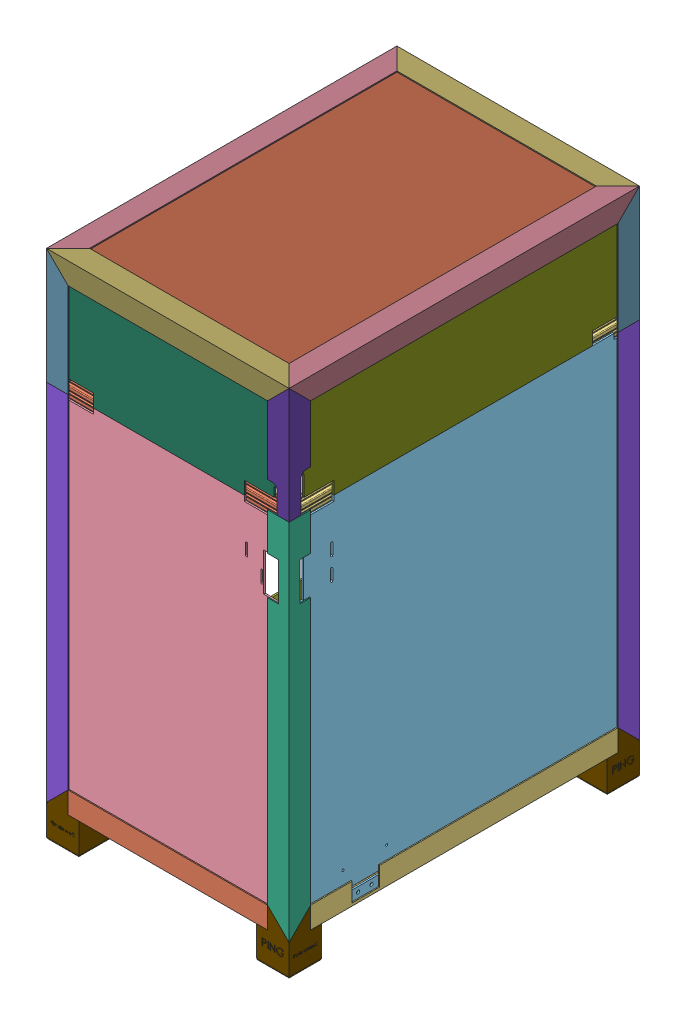
SolidWorks assembly carcasse, configuration Défaut. Lengths in mm.
Overall size (450.38 950 650.19).
53 component instances, 24 part files, 67 mates.
Components (placement in the parent):
- cadre-1: cadre [Défaut] at (-215.194 -19.8636 -400) size (448.16 24.28 648.16)
  - Blocks-1: Blocks [Défaut] at (-153.6103 82.5412 1245.1575) x (0 1 0) z (0 0 1) size (20 20 20)
  - Blocks-3: Blocks [Défaut] at (-153.6103 62.5412 625.1575) x (0 0 -1) z (0 1 0) size (20 20 20)
  - Blocks-4: Blocks [Défaut] at (246.3897 82.5412 645.1575) x (0 1 0) z (0 0 -1) size (20 20 20)
  - Blocks-5: Blocks [Défaut] at (246.3897 62.5412 1265.1575) x (0 0 1) z (0 1 0) size (20 20 20)
  - prof_20x20x400mm-1: prof_20x20x400mm [End Finishing_Non-Machined End Finish Options_Type_Single_] at (246.3897 72.5412 635.1575) x (0 0 1) z (-1 0 0) size (28.16 24.28 400)
  - prof_20x20x400mm-2: prof_20x20x400mm [End Finishing_Non-Machined End Finish Options_Type_Single_] at (246.3897 72.5412 1255.1575) x (0 0 1) z (-1 0 0) size (28.16 24.28 400)
  - prof_20x20x600mm-4: prof_20x20x600mm [End Finishing_Non-Machined End Finish Options_Type_Single_] at (256.3897 72.5412 645.1575) size (28.16 24.28 600)
  - prof_20x20x600mm-5: prof_20x20x600mm [End Finishing_Non-Machined End Finish Options_Type_Single_] at (-163.6103 72.5412 645.1575) size (28.16 24.28 600)
- prof_20x20x640mm-1: prof_20x20x640mm [End Finishing_Non-Machined End Finish Options_Type_Single_] at (41.1957 42.6776 235.1575) x (1 0 0) z (0 -1 0) size (28.16 24.28 640)
- prof_20x20x640mm-2: prof_20x20x640mm [End Finishing_Non-Machined End Finish Options_Type_Single_] at (41.1957 42.6776 855.1575) x (1 0 0) z (0 -1 0) size (28.16 24.28 640)
- prof_20x20x640mm-3: prof_20x20x640mm [End Finishing_Non-Machined End Finish Options_Type_Single_] at (-378.8043 42.6776 855.1575) x (1 0 0) z (0 -1 0) size (28.16 24.28 640)
- prof_20x20x640mm-4: prof_20x20x640mm [End Finishing_Non-Machined End Finish Options_Type_Single_] at (-378.8043 42.6776 235.1575) x (1 0 0) z (0 -1 0) size (28.16 24.28 640)
- cadre-2: cadre [Défaut] at (-122.4146 -534.7812 -400) x (-1 0 0) z (0 0 1) size (448.16 24.28 648.16)
  - Blocks-1: Blocks [Défaut] at (-153.6103 82.5412 1245.1575) x (0 1 0) z (0 0 1) size (20 20 20)
  - Blocks-3: Blocks [Défaut] at (-153.6103 62.5412 625.1575) x (0 0 -1) z (0 1 0) size (20 20 20)
  - Blocks-4: Blocks [Défaut] at (246.3897 82.5412 645.1575) x (0 1 0) z (0 0 -1) size (20 20 20)
  - Blocks-5: Blocks [Défaut] at (246.3897 62.5412 1265.1575) x (0 0 1) z (0 1 0) size (20 20 20)
  - prof_20x20x400mm-1: prof_20x20x400mm [End Finishing_Non-Machined End Finish Options_Type_Single_] at (246.3897 72.5412 635.1575) x (0 0 1) z (-1 0 0) size (28.16 24.28 400)
  - prof_20x20x400mm-2: prof_20x20x400mm [End Finishing_Non-Machined End Finish Options_Type_Single_] at (246.3897 72.5412 1255.1575) x (0 0 1) z (-1 0 0) size (28.16 24.28 400)
  - prof_20x20x600mm-4: prof_20x20x600mm [End Finishing_Non-Machined End Finish Options_Type_Single_] at (256.3897 72.5412 645.1575) size (28.16 24.28 600)
  - prof_20x20x600mm-5: prof_20x20x600mm [End Finishing_Non-Machined End Finish Options_Type_Single_] at (-163.6103 72.5412 645.1575) size (28.16 24.28 600)
- plaque_acrylique_680x670-2: plaque_acrylique_680x670 [Défaut] at (51.1957 -282.3224 525.1575) x (0 0 -1) z (1 0 0) size (640 670 3)
- plaque_acrylique_380x670_G-1: plaque_acrylique_380x670_G [Défaut] at (-138.8043 -282.3224 222.1575) size (440 670 3)
- plaque_acrylique_680x670_porte-1: plaque_acrylique_680x670_porte [Défaut] at (-391.8043 -282.3224 525.1575) x (0 0 -1) z (1 0 0) size (640 670 3)
- eclisse_40x40x670_bisote_x1-1: eclisse_40x40x670_bisote_x1 [Défaut] at (-373.8043 -622.3224 240.2711) size (40 675 40)
- eclisse_40x40x670_bisote_x1-2: eclisse_40x40x670_bisote_x1 [Défaut] at (-373.6907 -622.3224 850.1575) x (0 0 -1) z (1 0 0) size (40 675 40)
- eclisse_40x40x670_bisote_x1-4: eclisse_40x40x670_bisote_x1 [Défaut] at (36.0821 -622.3224 240.1575) x (0 0 1) z (-1 0 0) size (40 675 40)
- couvercle-1: couvercle [Défaut] at (303.0646 123.7676 738.5466) size (450 215 650)
  - plaque_acrylique_680x210-2: plaque_acrylique_680x210 [Défaut] at (-694.8689 33.91 -173.3892) x (0 0 -1) z (1 0 0) size (640 210 3)
  - plaque_acrylique_380x210-2: plaque_acrylique_380x210 [Défaut] at (-441.8689 33.91 -516.3892) size (440 210 3)
  - plaque_acrylique_380x680-1: plaque_acrylique_380x680 [Défaut] at (-441.8689 138.91 -173.3892) x (1 0 0) z (0 1 0) size (440 640 3)
  - eclisse_40x40x404_bisote_x2-1: eclisse_40x40x404_bisote_x2 [Défaut] at (-246.8689 123.7964 -498.3892) x (0 0 1) z (0 -1 0) size (40 450 40)
  - eclisse_40x40x704_bisote_x2-1: eclisse_40x40x704_bisote_x2 [Défaut] at (-266.9825 123.91 -518.3892) x (0 -1 0) z (-1 0 0) size (40 650 40)
  - eclisse_40x40x404_bisote_x2-2: eclisse_40x40x404_bisote_x2 [Défaut] at (-696.8689 123.7964 111.6108) x (0 0 -1) z (0 -1 0) size (40 450 40)
  - eclisse_40x40x704_bisote_x2-2: eclisse_40x40x704_bisote_x2 [Défaut] at (-676.8689 123.7964 -518.3892) x (1 0 0) z (0 -1 0) size (40 650 40)
  - eclisse_40x40x222_bisote_x1-1: eclisse_40x40x222_bisote_x1 [Défaut] at (-676.7552 143.91 -498.3892) x (0 0 1) z (1 0 0) size (40 215 40)
  - eclisse_40x40x222_bisote_x1-2: eclisse_40x40x222_bisote_x1 [Défaut] at (-266.8689 143.91 -498.2755) x (-1 0 0) z (0 0 1) size (40 215 40)
  - eclisse_40x40x222_bisote_x1-4: eclisse_40x40x222_bisote_x1 [Défaut] at (-676.8689 143.91 111.4972) x (1 0 0) z (0 0 -1) size (40 215 40)
  - plaque_acrylique_380x210_Moteur-1: plaque_acrylique_380x210_Moteur [Défaut] at (-441.8689 33.91 126.6108) size (440 210 3)
  - plaque_acrylique_680x210_moteur-1: plaque_acrylique_680x210_moteur [Défaut] at (-251.8689 33.91 -173.3892) x (0 0 -1) z (1 0 0) size (640 210 3)
  - eclisse_40x40x222_bisote_x1_Moteur-1: eclisse_40x40x222_bisote_x1_Moteur [Défaut] at (-266.9825 143.91 111.6108) x (0 0 -1) z (-1 0 0) size (40 215 40)
- Pied-1: Pied [Défaut] at (-3.8043 -622.3224 280.1575) x (-1 0 0) z (0 -1 0) size (60 60 100)
- Pied-2: Pied [Défaut] at (-3.8043 -622.3224 810.1575) x (0 0 -1) z (0 -1 0) size (60 60 100)
- Pied-3: Pied [Défaut] at (-333.8043 -622.3224 810.1575) x (1 0 0) z (0 -1 0) size (60 60 100)
- Pied-4: Pied [Défaut] at (-333.8043 -622.3224 280.1575) x (0 0 1) z (0 -1 0) size (60 60 100)
- eclisse_bas_40x40x704-2: eclisse_bas_40x40x704 [Défaut] at (-373.8043 -602.2087 830.1575) x (1 0 0) z (0 1 0) size (40 570 40)
- eclisse_bas_40x40x404-1: eclisse_bas_40x40x404 [Défaut] at (-353.8043 -602.2087 240.1575) x (0 0 1) z (0 1 0) size (40 370 40)
- eclisse_bas_40x40x404-2: eclisse_bas_40x40x404 [Défaut] at (16.1957 -602.2087 850.1575) x (0 0 -1) z (0 1 0) size (40 370 40)
- eclisse_bas_support_Z_40x40x704-1: eclisse_bas_support_Z_40x40x704 [Défaut] at (36.0821 -602.3224 830.1575) x (0 1 0) z (-1 0 0) size (40 570 40)
- plaque_acrylique_380x670_D-2: plaque_acrylique_380x670_D [Défaut] at (-198.8043 -282.3224 868.1575) x (-1 0 0) z (0 0 -1) size (440 670 3)
- plaque_acrylique_bas_380x680-1: plaque_acrylique_bas_380x680 [Défaut] at (-138.8043 -620.3224 565.1575) x (1 0 0) z (0 1 0) size (440 640 3)
- eclisse_40x40x670_bisote_x1-Moteur-1: eclisse_40x40x670_bisote_x1-Moteur [Défaut] at (36.1957 -622.3224 850.0438) x (-1 0 0) z (0 0 -1) size (40 675 40)
Mates (geometry in assembly coordinates):
- Coïncidente66: coincident anti-aligned: plane of plaque_acrylique_680x670_porte-1 through (-391.8043 -282.3224 525.1575) normal (-1 0 0); plane of eclisse_40x40x670_bisote_x1-1 through (-391.8043 52.6776 222.1575) normal (1 0 0)
- Coïncidente67: coincident aligned: plane of plaque_acrylique_680x670_porte-1 through (-388.8043 52.6776 865.1575) normal (0 1 0); plane of eclisse_40x40x670_bisote_x1-1 through (-373.8043 52.6776 240.2711) normal (0 1 0)
- Coïncidente68: coincident anti-aligned: plane of plaque_acrylique_680x670-2 through (54.1957 -282.3224 525.1575) normal (1 0 0); plane of eclisse_40x40x670_bisote_x1-4 through (54.1957 52.6776 222.1575) normal (-1 0 0)
- Coïncidente72: coincident anti-aligned: plane of plaque_acrylique_680x670_porte-1 through (-391.8043 -282.3224 525.1575) normal (-1 0 0); plane of eclisse_40x40x670_bisote_x1-2 through (-391.8043 52.6776 868.1575) normal (1 0 0)
- Coïncidente100: coincident: plane of plaque_acrylique_680x670_porte-1 through (-388.8043 52.6776 865.1575) normal (0 1 0); line of eclisse_40x40x670_bisote_x1-2 through (-391.8043 52.6776 868.1575) axis (0 0 -1)
- Coïncidente130: coincident anti-aligned: plane of eclisse_40x40x670_bisote_x1-2 through (196.1957 -622.3224 870.1575) normal (0 -0.707107 -0.707107); plane of Pied-3 through (-391.8043 -582.3224 830.1575) normal (0 0.707107 0.707107)
- Coïncidente132: coincident anti-aligned: plane of plaque_acrylique_680x670_porte-1 through (-391.8043 -282.3224 525.1575) normal (-1 0 0); plane of eclisse_bas_40x40x704-2 through (-391.8043 -620.3224 260.1575) normal (1 0 0)
- Coïncidente134: coincident anti-aligned: line of eclisse_40x40x670_bisote_x1-2 through (-393.8043 52.6776 830.1575) axis (0 -1 0); line of eclisse_bas_40x40x704-2 through (-393.8043 -622.3224 830.1575) axis (0 1 0)
- Coïncidente140: coincident anti-aligned: line of Pied-3 through (-353.8043 -582.3224 870.1575) axis (0 -1 0); line of eclisse_bas_40x40x404-2 through (-353.8043 -622.3224 870.1575) axis (0 1 0)
- Coïncidente142: coincident anti-aligned: plane of plaque_acrylique_680x670-2 through (54.1957 -282.3224 525.1575) normal (1 0 0); plane of eclisse_bas_support_Z_40x40x704-1 through (54.1957 -620.3224 260.1575) normal (-1 0 0)
- Coïncidente144: coincident anti-aligned: plane of Pied-2 through (54.1957 -582.3224 830.1575) normal (0 0 -1); plane of eclisse_bas_support_Z_40x40x704-1 through (36.0821 -602.3224 830.1575) normal (0 0 1)
- Coïncidente156: coincident anti-aligned: plane of eclisse_bas_40x40x404-2 through (-353.8043 -620.3224 868.1575) normal (0 0 -1); plane of plaque_acrylique_380x670_D-2 through (-198.8043 -282.3224 868.1575) normal (0 0 1)
- Coïncidente157: coincident anti-aligned: plane of eclisse_40x40x670_bisote_x1-2 through (-391.8043 52.6776 868.1575) normal (0 0 -1); plane of plaque_acrylique_380x670_D-2 through (-198.8043 -282.3224 868.1575) normal (0 0 1)
- Coïncidente163: coincident anti-aligned: plane of cadre-1/Blocks-1 through (-388.8043 42.6776 865.1575) normal (0 -1 0); plane of prof_20x20x640mm-3 through (-387.3043 42.6776 863.6575) normal (0 1 0)
- Coïncidente164: coincident aligned: plane of cadre-1/Blocks-1 through (-388.8043 42.6776 865.1575) normal (-1 0 0); plane of prof_20x20x640mm-3 through (-388.8043 -597.3224 858.9075) normal (-1 0 0)
- Coïncidente165: coincident aligned: plane of cadre-1/Blocks-1 through (-368.8043 62.6776 865.1575) normal (0 0 1); plane of prof_20x20x640mm-3 through (-382.5543 -597.3224 865.1575) normal (0 0 1)
- Coïncidente166: coincident anti-aligned: plane of prof_20x20x640mm-3 through (-387.3043 -597.3224 863.6575) normal (0 -1 0); plane of cadre-2/Blocks-5 through (-368.8043 -597.3224 865.1575) normal (0 1 0)
- Coïncidente167: coincident aligned: plane of prof_20x20x640mm-3 through (-382.5543 -597.3224 865.1575) normal (0 0 1); plane of cadre-2/Blocks-5 through (-388.8043 -617.3224 865.1575) normal (0 0 1)
- Coïncidente168: coincident aligned: plane of prof_20x20x640mm-3 through (-388.8043 -597.3224 858.9075) normal (-1 0 0); plane of cadre-2/Blocks-5 through (-388.8043 -617.3224 845.1575) normal (-1 0 0)
- Coïncidente169: coincident anti-aligned: plane of prof_20x20x640mm-2 through (32.6957 -597.3224 863.6575) normal (0 -1 0); plane of cadre-2/Blocks-1 through (51.1957 -597.3224 865.1575) normal (0 1 0)
- Coïncidente170: coincident aligned: plane of prof_20x20x640mm-2 through (37.4457 -597.3224 865.1575) normal (0 0 1); plane of cadre-2/Blocks-1 through (31.1957 -617.3224 865.1575) normal (0 0 1)
- Coïncidente171: coincident aligned: plane of prof_20x20x640mm-2 through (51.1957 -597.3224 858.9075) normal (1 0 0); plane of cadre-2/Blocks-1 through (51.1957 -597.3224 865.1575) normal (1 0 0)
- Coïncidente172: coincident anti-aligned: plane of prof_20x20x640mm-1 through (32.6957 -597.3224 243.6575) normal (0 -1 0); plane of cadre-2/Blocks-3 through (31.1957 -597.3224 225.1575) normal (0 1 0)
- Coïncidente173: coincident aligned: plane of prof_20x20x640mm-1 through (51.1957 -597.3224 238.9075) normal (1 0 0); plane of cadre-2/Blocks-3 through (51.1957 -617.3224 245.1575) normal (1 0 0)
- Coïncidente174: coincident aligned: plane of prof_20x20x640mm-1 through (44.9457 -597.3224 225.1575) normal (0 0 -1); plane of cadre-2/Blocks-3 through (51.1957 -617.3224 225.1575) normal (0 0 -1)
- Coïncidente175: coincident aligned: plane of cadre-1/Blocks-3 through (-388.8043 62.6776 245.1575) normal (-1 0 0); plane of prof_20x20x640mm-4 through (-388.8043 -597.3224 231.4075) normal (-1 0 0)
- Coïncidente176: coincident aligned: plane of cadre-1/Blocks-3 through (-388.8043 62.6776 225.1575) normal (0 0 -1); plane of prof_20x20x640mm-4 through (-382.5543 -597.3224 225.1575) normal (0 0 -1)
- Coïncidente177: coincident anti-aligned: plane of cadre-1/Blocks-3 through (-368.8043 42.6776 225.1575) normal (0 -1 0); plane of prof_20x20x640mm-4 through (-387.3043 42.6776 243.6575) normal (0 1 0)
- Coïncidente183: coincident aligned: plane of prof_20x20x640mm-2 through (51.1957 -597.3224 858.9075) normal (1 0 0); plane of plaque_acrylique_380x670_D-2 through (51.1957 52.6776 865.1575) normal (1 0 0)
- Coïncidente186: coincident aligned: plane of cadre-1/prof_20x20x400mm-2 through (-368.8043 56.4276 865.1575) normal (0 0 1); plane of plaque_acrylique_680x670-2 through (54.1957 52.6776 865.1575) normal (0 0 1)
- Coïncidente187: coincident aligned: plane of cadre-1/prof_20x20x400mm-1 through (-368.8043 48.9276 225.1575) normal (0 0 -1); plane of plaque_acrylique_680x670_porte-1 through (-388.8043 52.6776 225.1575) normal (0 0 -1)
- Coïncidente191: coincident anti-aligned: plane of cadre-2/prof_20x20x400mm-1 through (31.1957 -617.3224 238.9075) normal (0 -1 0); plane of plaque_acrylique_bas_380x680-1 through (-138.8043 -617.3224 565.1575) normal (0 1 0)
- Coïncidente192: coincident aligned: plane of cadre-2/prof_20x20x400mm-2 through (31.1957 -611.0724 865.1575) normal (0 0 1); plane of plaque_acrylique_bas_380x680-1 through (-388.8043 -617.3224 865.1575) normal (0 0 1)
- Coïncidente199: coincident anti-aligned: line of eclisse_40x40x670_bisote_x1-4 through (56.1957 -622.3224 220.1575) axis (0 0.707107 0.707107); line of Pied-1 through (56.1957 -582.3224 260.1575) axis (0 -0.707107 -0.707107)
- Coïncidente201: coincident anti-aligned: plane of plaque_acrylique_680x670-2 through (54.1957 -282.3224 525.1575) normal (1 0 0); plane of Pied-2 through (54.1957 -582.3224 868.1575) normal (-1 0 0)
- Coïncidente204: coincident anti-aligned: plane of prof_20x20x640mm-1 through (44.9457 -597.3224 225.1575) normal (0 0 -1); plane of plaque_acrylique_380x670_G-1 through (-138.8043 -282.3224 225.1575) normal (0 0 1)
- Coïncidente205: coincident aligned: plane of cadre-2/prof_20x20x400mm-1 through (31.1957 -617.3224 231.4075) normal (0 -1 0); plane of plaque_acrylique_380x670_G-1 through (-388.8043 -617.3224 225.1575) normal (0 -1 0)
- Coïncidente206: coincident aligned: plane of prof_20x20x640mm-1 through (51.1957 -597.3224 231.4075) normal (1 0 0); plane of plaque_acrylique_380x670_G-1 through (51.1957 52.6776 225.1575) normal (1 0 0)
- Coïncidente207: coincident anti-aligned: plane of prof_20x20x640mm-4 through (-388.8043 -597.3224 231.4075) normal (-1 0 0); plane of plaque_acrylique_680x670_porte-1 through (-388.8043 -282.3224 525.1575) normal (1 0 0)
- Coïncidente208: coincident anti-aligned: plane of plaque_acrylique_380x670_G-1 through (-138.8043 -282.3224 222.1575) normal (0 0 -1); plane of eclisse_40x40x670_bisote_x1-1 through (-391.8043 52.6776 222.1575) normal (0 0 1)
- Coïncidente210: coincident anti-aligned: plane of plaque_acrylique_380x670_G-1 through (-138.8043 -282.3224 222.1575) normal (0 0 -1); plane of eclisse_40x40x670_bisote_x1-4 through (54.1957 52.6776 222.1575) normal (0 0 1)
- Parallèle4: parallel anti-aligned: line of eclisse_40x40x670_bisote_x1-1 through (-393.8043 -622.3224 220.1575) axis (0.707107 0.707107 0); line of Pied-4 through (-353.8043 -582.3224 220.1575) axis (-0.707107 -0.707107 0)
- Coïncidente218: coincident: plane of cadre-2/prof_20x20x400mm-2 through (31.1957 -617.3224 858.9075) normal (0 -1 0); line of plaque_acrylique_380x670_D-2 through (51.1957 -617.3224 868.1575) axis (-1 0 0)
- Coïncidente223: coincident anti-aligned: plane of eclisse_bas_support_Z_40x40x704-1 through (54.1957 -620.3224 260.1575) normal (0 1 0); plane of plaque_acrylique_bas_380x680-1 through (-138.8043 -620.3224 565.1575) normal (0 -1 0)
- Coïncidente224: coincident anti-aligned: plane of eclisse_bas_40x40x704-2 through (-391.8043 -620.3224 260.1575) normal (0 1 0); plane of plaque_acrylique_bas_380x680-1 through (-138.8043 -620.3224 565.1575) normal (0 -1 0)
- Coïncidente225: coincident anti-aligned: plane of plaque_acrylique_380x670_G-1 through (-138.8043 -282.3224 222.1575) normal (0 0 -1); plane of eclisse_bas_40x40x404-1 through (16.1957 -620.3224 222.1575) normal (0 0 1)
- Coïncidente226: coincident anti-aligned: plane of eclisse_bas_40x40x404-1 through (16.1957 -620.3224 222.1575) normal (0 1 0); plane of plaque_acrylique_bas_380x680-1 through (-138.8043 -620.3224 565.1575) normal (0 -1 0)
- Coïncidente227: coincident anti-aligned: plane of Pied-1 through (16.1957 -582.3224 222.1575) normal (-1 0 0); plane of eclisse_bas_40x40x404-1 through (16.1957 -602.2087 240.1575) normal (1 0 0)
- Coïncidente228: coincident anti-aligned: plane of plaque_acrylique_680x670_porte-1 through (-391.8043 -282.3224 525.1575) normal (-1 0 0); plane of Pied-3 through (-391.8043 -582.3224 830.1575) normal (1 0 0)
- Coïncidente229: coincident anti-aligned: plane of plaque_acrylique_380x670_G-1 through (-138.8043 -282.3224 222.1575) normal (0 0 -1); plane of Pied-4 through (-353.8043 -582.3224 222.1575) normal (0 0 1)
- Coïncidente230: coincident anti-aligned: plane of plaque_acrylique_680x670_porte-1 through (-391.8043 -282.3224 525.1575) normal (-1 0 0); plane of Pied-4 through (-391.8043 -582.3224 222.1575) normal (1 0 0)
- Coïncidente231: coincident anti-aligned: plane of plaque_acrylique_380x670_G-1 through (-138.8043 -282.3224 222.1575) normal (0 0 -1); plane of Pied-1 through (54.1957 -582.3224 222.1575) normal (0 0 1)
- Coïncidente232: coincident aligned: plane of plaque_acrylique_380x670_G-1 through (-138.8043 -282.3224 222.1575) normal (0 0 -1); plane of couvercle-1/plaque_acrylique_380x210-2 through (-138.8043 157.6776 222.1575) normal (0 0 -1)
- Coïncidente233: coincident aligned: plane of couvercle-1/plaque_acrylique_380x210_Moteur-1 through (-138.8043 157.6776 868.1575) normal (0 0 1); plane of plaque_acrylique_380x670_D-2 through (-198.8043 -282.3224 868.1575) normal (0 0 1)
- Coïncidente234: coincident anti-aligned: line of plaque_acrylique_680x670-2 through (54.1957 52.6776 265.1575) axis (0 0 1); line of couvercle-1/plaque_acrylique_680x210_moteur-1 through (54.1957 52.6776 785.1575) axis (0 0 -1)
- Coïncidente235: coincident aligned: plane of plaque_acrylique_680x670-2 through (54.1957 -282.3224 525.1575) normal (1 0 0); plane of couvercle-1/plaque_acrylique_680x210_moteur-1 through (54.1957 157.6776 565.1575) normal (1 0 0)
- Coïncidente236: coincident anti-aligned: plane of plaque_acrylique_680x670-2 through (54.1957 -282.3224 525.1575) normal (1 0 0); plane of eclisse_40x40x670_bisote_x1-Moteur-1 through (54.1957 52.6776 868.1575) normal (-1 0 0)
- Coïncidente237: coincident anti-aligned: plane of plaque_acrylique_380x670_D-2 through (-198.8043 -282.3224 868.1575) normal (0 0 1); plane of eclisse_40x40x670_bisote_x1-Moteur-1 through (54.1957 52.6776 868.1575) normal (0 0 -1)
- Coïncidente238: coincident anti-aligned: line of Pied-2 through (16.1957 -582.3224 870.1575) axis (0.707107 -0.707107 0); line of eclisse_40x40x670_bisote_x1-Moteur-1 through (56.1957 -622.3224 870.1575) axis (-0.707107 0.707107 0)
- Coïncidente239: coincident anti-aligned: plane of plaque_acrylique_680x670_porte-1 through (-388.8043 -282.3224 525.1575) normal (1 0 0); plane of plaque_acrylique_bas_380x680-1 through (-388.8043 -617.3224 225.1575) normal (-1 0 0)
- Coïncidente240: coincident anti-aligned: plane of cadre-2/prof_20x20x600mm-5 through (51.1957 -611.0724 845.1575) normal (1 0 0); plane of plaque_acrylique_680x670-2 through (51.1957 -282.3224 525.1575) normal (-1 0 0)
- Coïncidente241: coincident aligned: plane of cadre-2/prof_20x20x600mm-5 through (44.9457 -617.3224 845.1575) normal (0 -1 0); plane of plaque_acrylique_680x670-2 through (54.1957 -617.3224 865.1575) normal (0 -1 0)
- Coïncidente242: coincident aligned: plane of cadre-2/prof_20x20x600mm-4 through (-382.5543 -617.3224 845.1575) normal (0 -1 0); plane of plaque_acrylique_680x670_porte-1 through (-388.8043 -617.3224 865.1575) normal (0 -1 0)
- Coïncidente243: coincident anti-aligned: plane of eclisse_bas_40x40x404-2 through (-353.8043 -620.3224 868.1575) normal (0 1 0); plane of plaque_acrylique_bas_380x680-1 through (-138.8043 -620.3224 565.1575) normal (0 -1 0)
- Coïncidente244: coincident anti-aligned: plane of Pied-2 through (-3.8043 -622.3224 810.1575) normal (0 1 0); plane of eclisse_bas_40x40x404-2 through (-353.8043 -622.3224 870.1575) normal (0 -1 0)
- Coïncidente245: coincident anti-aligned: plane of Pied-4 through (-333.8043 -622.3224 280.1575) normal (0 1 0); plane of eclisse_bas_40x40x704-2 through (-393.8043 -622.3224 260.1575) normal (0 -1 0)
- Coïncidente246: coincident anti-aligned: plane of Pied-1 through (-3.8043 -622.3224 280.1575) normal (0 1 0); plane of eclisse_bas_40x40x404-1 through (16.1957 -622.3224 220.1575) normal (0 -1 0)
